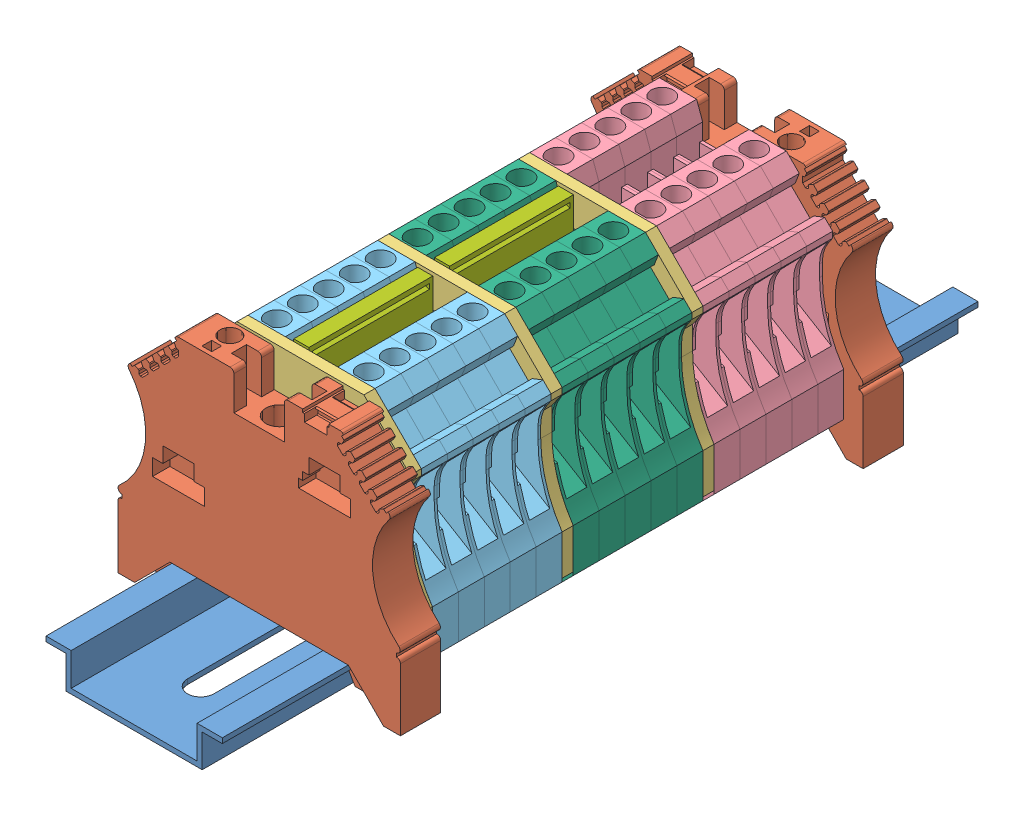
SolidWorks assembly 5xLNPE, configuration Standard. Lengths in mm.
Overall size (56.97 56.59 150).
23 component instances, 7 part files, 79 mates.
Components (placement in the parent):
- Hutschiene-1: Hutschiene [150] at (-17.5 -7.5 -150) size (35 7.5 150)
- WEW_35_2-1: WEW_35_2 [Standard] at (-45.75 -7 -124.85) x (0 0 1) z (0 1 0) size (8 56.1 46.5)
- WEW_35_2-2: WEW_35_2 [Standard] at (10.35 -7 -25) x (0 0 -1) z (0 1 0) size (8 56.1 46.5)
- D_UT_2.5_10-1: D_UT_2.5_10 [Standard] at (-46.4297 58.45 -35.2) size (47 39.8 2.2)
- D_UT_2.5_10-2: D_UT_2.5_10 [Standard] at (-46.4297 58.45 -63.15) size (47 39.8 2.2)
- D_UT_2.5_10-3: D_UT_2.5_10 [Standard] at (-46.4297 58.45 -91.1) size (47 39.8 2.2)
- UT_2.5_PE-1: UT_2.5_PE [Standard] at (-48.6989 10.6178 -91.1) x (0.992546 -0.121869 0) z (0 0 1) size (49.27 50.96 5.15)
- UT_2.5_PE-2: UT_2.5_PE [Standard] at (-48.6989 10.6178 -96.25) x (0.992546 -0.121869 0) z (0 0 1) size (49.27 50.96 5.15)
- UT_2.5_PE-3: UT_2.5_PE [Standard] at (-48.6989 10.6178 -101.4) x (0.992546 -0.121869 0) z (0 0 1) size (49.27 50.96 5.15)
- UT_2.5_PE-4: UT_2.5_PE [Standard] at (-48.6989 10.6178 -106.55) x (0.992546 -0.121869 0) z (0 0 1) size (49.27 50.96 5.15)
- UT_2.5_PE-5: UT_2.5_PE [Standard] at (-48.6989 10.6178 -111.7) x (0.992546 -0.121869 0) z (0 0 1) size (49.27 50.96 5.15)
- UT_2.5-1: UT_2.5 [Standard] at (-48.6989 10.6178 -35.2) x (0.992546 -0.121869 0) z (0 0 1) size (49.27 50.96 5.15)
- UT_2.5-2: UT_2.5 [Standard] at (-48.6989 10.6178 -40.35) x (0.992546 -0.121869 0) z (0 0 1) size (49.27 50.96 5.15)
- UT_2.5-3: UT_2.5 [Standard] at (-48.6989 10.6178 -45.5) x (0.992546 -0.121869 0) z (0 0 1) size (49.27 50.96 5.15)
- UT_2.5-4: UT_2.5 [Standard] at (-48.6989 10.6178 -50.65) x (0.992546 -0.121869 0) z (0 0 1) size (49.27 50.96 5.15)
- UT_2.5-5: UT_2.5 [Standard] at (-48.6989 10.6178 -55.8) x (0.992546 -0.121869 0) z (0 0 1) size (49.27 50.96 5.15)
- UT_2.5_BU-1: UT_2.5_BU [Standard] at (-48.6989 10.6178 -63.15) x (0.992546 -0.121869 0) z (0 0 1) size (49.27 50.96 5.15)
- UT_2.5_BU-2: UT_2.5_BU [Standard] at (-48.6989 10.6178 -68.3) x (0.992546 -0.121869 0) z (0 0 1) size (49.27 50.96 5.15)
- UT_2.5_BU-3: UT_2.5_BU [Standard] at (-48.6989 10.6178 -73.45) x (0.992546 -0.121869 0) z (0 0 1) size (49.27 50.96 5.15)
- UT_2.5_BU-4: UT_2.5_BU [Standard] at (-48.6989 10.6178 -78.6) x (0.992546 -0.121869 0) z (0 0 1) size (49.27 50.96 5.15)
- UT_2.5_BU-5: UT_2.5_BU [Standard] at (-48.6989 10.6178 -83.75) x (0.992546 -0.121869 0) z (0 0 1) size (49.27 50.96 5.15)
- FBS_5_5-1: FBS_5_5 [Standard] at (-24.1072 48.875 -94.035) size (3 22.98 24.6)
- FBS_5_5-2: FBS_5_5 [Standard] at (-24.1072 48.875 -121.985) size (3 22.98 24.6)
Mates (geometry in assembly coordinates):
- Deckungsgleich1: coincident aligned: plane of Hutschiene-1 through (-17.5 -7.5 0) normal (0 0 1); plane of assembly through (0 0 0) normal (0 0 1)
- Deckungsgleich2: coincident aligned: plane of Hutschiene-1 through (-30 0 0) normal (0 1 0); plane of assembly through (0 0 0) normal (0 1 0)
- Deckungsgleich3: coincident aligned: plane of Hutschiene-1 through (0 -1 0) normal (1 0 0); plane of assembly through (0 0 0) normal (1 0 0)
- Abstand1: distance = 25 mm aligned: plane of WEW_35_2-2 through (-17.7 0 -25) normal (0 0 1); plane of Hutschiene-1 through (-17.5 -7.5 0) normal (0 0 1)
- Deckungsgleich70: coincident anti-aligned: plane of Hutschiene-1 through (0 0 0) normal (0 1 0); plane of ? through (-54.05 0 -193.75) normal (0 -1 0)
- Deckungsgleich71: coincident anti-aligned: plane of Hutschiene-1 through (-30 0 0) normal (0 1 0); plane of ? through (-54.05 0 -238.75) normal (0 -1 0)
- Deckungsgleich72: coincident anti-aligned: plane of Hutschiene-1 through (-30 0 0) normal (0 1 0); plane of ? through (-54.05 0 -283.75) normal (0 -1 0)
- Deckungsgleich73: coincident anti-aligned: plane of Hutschiene-1 through (0 -1 0) normal (1 0 0); plane of ? through (0 8.9 -167.85) normal (-1 0 0)
- Deckungsgleich74: coincident anti-aligned: plane of Hutschiene-1 through (0 -1 0) normal (1 0 0); plane of ? through (0 8.9 -212.85) normal (-1 0 0)
- Deckungsgleich75: coincident anti-aligned: plane of Hutschiene-1 through (0 -1 0) normal (1 0 0); plane of ? through (0 8.9 -257.85) normal (-1 0 0)
- Deckungsgleich77: coincident anti-aligned: plane of ? through (-17.75 2.45 -211.85) normal (0 0 -1); plane of ? through (-17.75 2.45 -211.85) normal (0 0 1)
- Deckungsgleich78: coincident anti-aligned: plane of ? through (-17.75 2.45 -256.85) normal (0 0 -1); plane of ? through (-17.75 2.45 -256.85) normal (0 0 1)
- Deckungsgleich81: coincident anti-aligned: plane of Hutschiene-1 through (-30 0 0) normal (0 1 0); plane of WEW_35_2-2 through (-35.4 0 -33) normal (0 -1 0)
- Deckungsgleich82: coincident anti-aligned: plane of Hutschiene-1 through (-30 0 0) normal (0 1 0); plane of UT_2.5-1 through (-7.7 0 -35.2) normal (0 -1 0)
- Deckungsgleich83: coincident anti-aligned: plane of Hutschiene-1 through (-30 0 0) normal (0 1 0); plane of UT_2.5-2 through (-7.7 0 -40.35) normal (0 -1 0)
- Deckungsgleich84: coincident anti-aligned: plane of Hutschiene-1 through (-30 0 0) normal (0 1 0); plane of UT_2.5-3 through (-7.7 0 -45.5) normal (0 -1 0)
- Deckungsgleich85: coincident anti-aligned: plane of Hutschiene-1 through (-30 0 0) normal (0 1 0); plane of UT_2.5-4 through (-7.7 0 -50.65) normal (0 -1 0)
- Deckungsgleich86: coincident anti-aligned: plane of Hutschiene-1 through (-30 0 0) normal (0 1 0); plane of UT_2.5-5 through (-7.7 0 -55.8) normal (0 -1 0)
- Deckungsgleich87: coincident aligned: plane of D_UT_2.5_10-1 through (4.3 30.8 -34.1) normal (1 0 0); plane of UT_2.5-1 through (4.3 30.8 -35.2) normal (1 0 0)
- Deckungsgleich88: coincident aligned: line of D_UT_2.5_10-1 through (4.3 29.6 -35.2) axis (0 0 1); line of UT_2.5-1 through (4.3 29.6 -40.35) axis (0 0 1)
- Deckungsgleich89: coincident anti-aligned: plane of D_UT_2.5_10-1 through (8.926 -3.78 -35.2) normal (0 0 -1); plane of UT_2.5-1 through (0 0 -35.2) normal (0 0 1)
- Deckungsgleich90: coincident anti-aligned: plane of UT_2.5-1 through (0 0 -40.35) normal (0 0 -1); plane of UT_2.5-2 through (0 0 -40.35) normal (0 0 1)
- Deckungsgleich91: coincident anti-aligned: plane of UT_2.5-2 through (0 0 -45.5) normal (0 0 -1); plane of UT_2.5-3 through (0 0 -45.5) normal (0 0 1)
- Deckungsgleich92: coincident anti-aligned: plane of UT_2.5-3 through (0 0 -50.65) normal (0 0 -1); plane of UT_2.5-4 through (0 0 -50.65) normal (0 0 1)
- Deckungsgleich93: coincident anti-aligned: plane of UT_2.5-4 through (0 0 -55.8) normal (0 0 -1); plane of UT_2.5-5 through (0 0 -55.8) normal (0 0 1)
- Deckungsgleich94: coincident anti-aligned: plane of Hutschiene-1 through (0 -1 0) normal (1 0 0); plane of UT_2.5-1 through (0 -1.1 -35.2) normal (-1 0 0)
- Deckungsgleich95: coincident anti-aligned: plane of Hutschiene-1 through (0 -1 0) normal (1 0 0); plane of UT_2.5-2 through (0 -1.1 -40.35) normal (-1 0 0)
- Deckungsgleich96: coincident anti-aligned: plane of Hutschiene-1 through (0 -1 0) normal (1 0 0); plane of UT_2.5-3 through (0 -1.1 -45.5) normal (-1 0 0)
- Deckungsgleich97: coincident anti-aligned: plane of Hutschiene-1 through (0 -1 0) normal (1 0 0); plane of UT_2.5-4 through (0 -1.1 -50.65) normal (-1 0 0)
- Deckungsgleich98: coincident anti-aligned: plane of Hutschiene-1 through (0 -1 0) normal (1 0 0); plane of UT_2.5-5 through (0 -1.1 -55.8) normal (-1 0 0)
- Deckungsgleich99: coincident anti-aligned: plane of WEW_35_2-2 through (-17.7 0 -33) normal (0 0 -1); plane of D_UT_2.5_10-1 through (-31.3534 31.331 -33) normal (0 0 1)
- Deckungsgleich101: coincident: plane of Hutschiene-1 through (0 -1 0) normal (1 0 0); line of WEW_35_2-2 through (0 0 -33) axis (0 0 1)
- Deckungsgleich102: coincident anti-aligned: plane of UT_2.5-1 through (-18.35 21.85 -35.675) normal (0 0 -1); plane of FBS_5_5-1 through (-18.5 39.7 -35.675) normal (0 0 1)
- Deckungsgleich103: coincident anti-aligned: plane of UT_2.5-2 through (-21.5 36.703 -40.35) normal (1 0 0); plane of FBS_5_5-1 through (-21.5 38.7586 -49.6095) normal (-1 0 0)
- Deckungsgleich104: coincident aligned: plane of UT_2.5-1 through (-30.1 40 -35.2) normal (0 1 0); plane of FBS_5_5-1 through (-18.5 40 -46.075) normal (0 1 0)
- Deckungsgleich105: coincident anti-aligned: plane of D_UT_2.5_10-2 through (8.926 -3.78 -63.15) normal (0 0 -1); plane of UT_2.5_BU-1 through (0 0 -63.15) normal (0 0 1)
- Deckungsgleich106: coincident anti-aligned: plane of UT_2.5_BU-1 through (0 0 -68.3) normal (0 0 -1); plane of UT_2.5_BU-2 through (0 0 -68.3) normal (0 0 1)
- Deckungsgleich107: coincident anti-aligned: plane of UT_2.5_BU-2 through (0 0 -73.45) normal (0 0 -1); plane of UT_2.5_BU-3 through (0 0 -73.45) normal (0 0 1)
- Deckungsgleich108: coincident anti-aligned: plane of UT_2.5_BU-3 through (0 0 -78.6) normal (0 0 -1); plane of UT_2.5_BU-4 through (0 0 -78.6) normal (0 0 1)
- Deckungsgleich109: coincident anti-aligned: plane of UT_2.5_BU-4 through (0 0 -83.75) normal (0 0 -1); plane of UT_2.5_BU-5 through (0 0 -83.75) normal (0 0 1)
- Deckungsgleich110: coincident anti-aligned: plane of Hutschiene-1 through (-30 0 0) normal (0 1 0); plane of UT_2.5_BU-1 through (-7.7 0 -63.15) normal (0 -1 0)
- Deckungsgleich111: coincident anti-aligned: plane of Hutschiene-1 through (-30 0 0) normal (0 1 0); plane of UT_2.5_BU-2 through (-7.7 0 -68.3) normal (0 -1 0)
- Deckungsgleich112: coincident anti-aligned: plane of Hutschiene-1 through (-30 0 0) normal (0 1 0); plane of UT_2.5_BU-3 through (-7.7 0 -73.45) normal (0 -1 0)
- Deckungsgleich113: coincident anti-aligned: plane of Hutschiene-1 through (-30 0 0) normal (0 1 0); plane of UT_2.5_BU-4 through (-7.7 0 -78.6) normal (0 -1 0)
- Deckungsgleich114: coincident anti-aligned: plane of Hutschiene-1 through (-30 0 0) normal (0 1 0); plane of UT_2.5_BU-5 through (-7.7 0 -83.75) normal (0 -1 0)
- Deckungsgleich115: coincident aligned: plane of D_UT_2.5_10-2 through (4.3 30.8 -62.05) normal (1 0 0); plane of UT_2.5_BU-1 through (4.3 30.8 -63.15) normal (1 0 0)
- Deckungsgleich116: coincident aligned: line of D_UT_2.5_10-2 through (4.3 29.6 -63.15) axis (0 0 1); line of UT_2.5_BU-1 through (4.3 29.6 -68.3) axis (0 0 1)
- Deckungsgleich117: coincident anti-aligned: plane of Hutschiene-1 through (0 -1 0) normal (1 0 0); plane of UT_2.5_BU-1 through (0 -1.1 -63.15) normal (-1 0 0)
- Deckungsgleich118: coincident anti-aligned: plane of Hutschiene-1 through (0 -1 0) normal (1 0 0); plane of UT_2.5_BU-2 through (0 -1.1 -68.3) normal (-1 0 0)
- Deckungsgleich119: coincident anti-aligned: plane of Hutschiene-1 through (0 -1 0) normal (1 0 0); plane of UT_2.5_BU-3 through (0 -1.1 -73.45) normal (-1 0 0)
- Deckungsgleich120: coincident anti-aligned: plane of Hutschiene-1 through (0 -1 0) normal (1 0 0); plane of UT_2.5_BU-4 through (0 -1.1 -78.6) normal (-1 0 0)
- Deckungsgleich121: coincident anti-aligned: plane of Hutschiene-1 through (0 -1 0) normal (1 0 0); plane of UT_2.5_BU-5 through (0 -1.1 -83.75) normal (-1 0 0)
- Deckungsgleich122: coincident anti-aligned: plane of D_UT_2.5_10-2 through (-31.3534 31.331 -60.95) normal (0 0 1); plane of UT_2.5-5 through (0 0 -60.95) normal (0 0 -1)
- Deckungsgleich123: coincident anti-aligned: plane of UT_2.5_BU-1 through (-18.35 21.85 -63.625) normal (0 0 -1); plane of FBS_5_5-2 through (-18.5 39.7 -63.625) normal (0 0 1)
- Deckungsgleich124: coincident anti-aligned: plane of UT_2.5_BU-1 through (-21.5 36.703 -63.15) normal (1 0 0); plane of FBS_5_5-2 through (-21.5 38.7586 -77.5595) normal (-1 0 0)
- Deckungsgleich125: coincident aligned: plane of UT_2.5_BU-1 through (-30.1 40 -63.15) normal (0 1 0); plane of FBS_5_5-2 through (-18.5 40 -74.025) normal (0 1 0)
- Deckungsgleich126: coincident anti-aligned: plane of D_UT_2.5_10-3 through (8.926 -3.78 -91.1) normal (0 0 -1); plane of UT_2.5_PE-1 through (0 0 -91.1) normal (0 0 1)
- Deckungsgleich127: coincident anti-aligned: plane of UT_2.5_PE-1 through (0 0 -96.25) normal (0 0 -1); plane of UT_2.5_PE-2 through (0 0 -96.25) normal (0 0 1)
- Deckungsgleich128: coincident anti-aligned: plane of UT_2.5_PE-2 through (0 0 -101.4) normal (0 0 -1); plane of UT_2.5_PE-3 through (0 0 -101.4) normal (0 0 1)
- Deckungsgleich129: coincident anti-aligned: plane of UT_2.5_PE-3 through (0 0 -106.55) normal (0 0 -1); plane of UT_2.5_PE-4 through (0 0 -106.55) normal (0 0 1)
- Deckungsgleich130: coincident anti-aligned: plane of UT_2.5_PE-4 through (0 0 -111.7) normal (0 0 -1); plane of UT_2.5_PE-5 through (0 0 -111.7) normal (0 0 1)
- Deckungsgleich131: coincident aligned: plane of D_UT_2.5_10-3 through (4.3 30.8 -90) normal (1 0 0); plane of UT_2.5_PE-1 through (4.3 30.8 -91.1) normal (1 0 0)
- Deckungsgleich132: coincident aligned: line of D_UT_2.5_10-3 through (4.3 30.8 -91.1) axis (0 0 1); line of UT_2.5_PE-1 through (4.3 30.8 -96.25) axis (0 0 1)
- Deckungsgleich133: coincident anti-aligned: plane of Hutschiene-1 through (-30 0 0) normal (0 1 0); plane of UT_2.5_PE-5 through (-7.7 0 -111.7) normal (0 -1 0)
- Deckungsgleich134: coincident anti-aligned: plane of Hutschiene-1 through (-30 0 0) normal (0 1 0); plane of UT_2.5_PE-4 through (-7.7 0 -106.55) normal (0 -1 0)
- Deckungsgleich135: coincident anti-aligned: plane of Hutschiene-1 through (-30 0 0) normal (0 1 0); plane of UT_2.5_PE-3 through (-7.7 0 -101.4) normal (0 -1 0)
- Deckungsgleich136: coincident anti-aligned: plane of Hutschiene-1 through (-30 0 0) normal (0 1 0); plane of UT_2.5_PE-2 through (-7.7 0 -96.25) normal (0 -1 0)
- Deckungsgleich137: coincident anti-aligned: plane of Hutschiene-1 through (-30 0 0) normal (0 1 0); plane of UT_2.5_PE-1 through (-7.7 0 -91.1) normal (0 -1 0)
- Deckungsgleich138: coincident anti-aligned: plane of Hutschiene-1 through (0 -1 0) normal (1 0 0); plane of UT_2.5_PE-1 through (0 -1.1 -91.1) normal (-1 0 0)
- Deckungsgleich139: coincident anti-aligned: plane of Hutschiene-1 through (0 -1 0) normal (1 0 0); plane of UT_2.5_PE-2 through (0 -1.1 -96.25) normal (-1 0 0)
- Deckungsgleich140: coincident anti-aligned: plane of Hutschiene-1 through (0 -1 0) normal (1 0 0); plane of UT_2.5_PE-3 through (0 -1.1 -101.4) normal (-1 0 0)
- Deckungsgleich141: coincident anti-aligned: plane of Hutschiene-1 through (0 -1 0) normal (1 0 0); plane of UT_2.5_PE-4 through (0 -1.1 -106.55) normal (-1 0 0)
- Deckungsgleich142: coincident anti-aligned: plane of Hutschiene-1 through (0 -1 0) normal (1 0 0); plane of UT_2.5_PE-5 through (0 -1.1 -111.7) normal (-1 0 0)
- Deckungsgleich143: coincident anti-aligned: plane of D_UT_2.5_10-3 through (-31.3534 31.331 -88.9) normal (0 0 1); plane of UT_2.5_BU-5 through (0 0 -88.9) normal (0 0 -1)
- Deckungsgleich144: coincident anti-aligned: plane of UT_2.5_PE-5 through (0 0 -166.85) normal (0 0 -1); plane of ? through (-17.75 2.45 -166.85) normal (0 0 1)
- Deckungsgleich145: coincident anti-aligned: plane of WEW_35_2-1 through (-17.7 0 -301.85) normal (0 0 1); plane of ? through (-17.75 2.45 -301.85) normal (0 0 -1)
- Deckungsgleich146: coincident anti-aligned: plane of Hutschiene-1 through (0 0 0) normal (0 1 0); plane of WEW_35_2-1 through (0 0 -116.85) normal (0 -1 0)
- Deckungsgleich147: coincident anti-aligned: line of Hutschiene-1 through (0 0 0) axis (0 0 -1); line of WEW_35_2-1 through (0 0 -124.85) axis (0 0 1)
- Deckungsgleich148: coincident anti-aligned: plane of WEW_35_2-1 through (-17.7 0 -116.85) normal (0 0 1); plane of UT_2.5_PE-5 through (0 0 -116.85) normal (0 0 -1)
